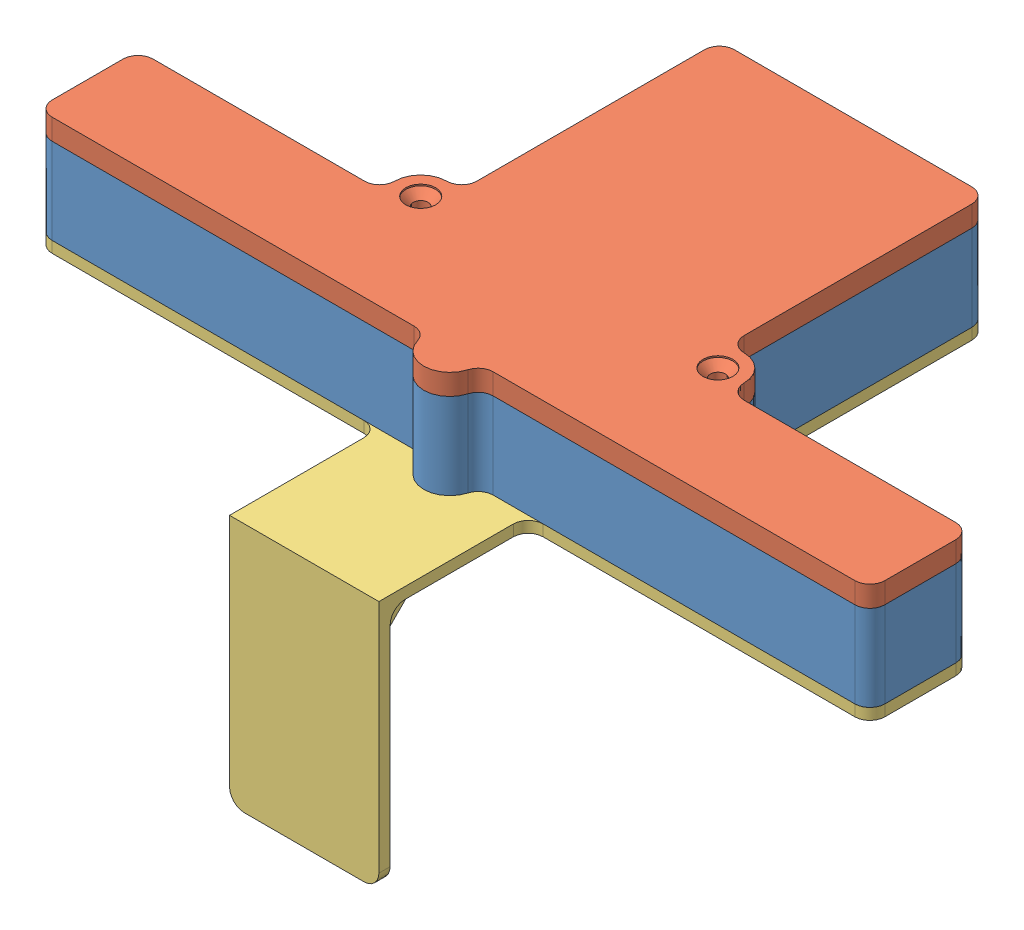
SolidWorks assembly frame, configuration Default. Lengths in mm.
Overall size (111.5 47.8 73.5).
3 component instances, 3 part files, 8 mates.
Components (placement in the parent):
- frame-front-1: frame-front [Default] at origin size (111.5 11.5 57.5)
- frame-screen-1: frame-screen [Default] at (0 11.5 0) x (1 0 0) z (0 1 0) size (111.5 57.5 2.8)
- frame-rear-1: frame-rear [Default] x (-1 0 0) z (0 -1 0) size (111.5 73.5 33.5)
Mates (geometry in assembly coordinates):
- InPlace1: in place: plane of frame-front-1 through (0 10.7 0) normal (0 1 0); plane of ? through (0 10.7 0) normal (0 1 0); moOrthogonalPlaneRef_w of frame-front-1 through (0 10.7 0) normal (0 1 0); plane of ? through (0 10.7 0) normal (0 0 -1); plane of frame-front-1 through (0 10.7 0) normal (0 1 0); plane of ? through (0 10.7 0) normal (1 0 0); plane of frame-front-1 through (0 11.5 0) normal (0 1 0); unknown of frame-screen-1
- Coincident1: coincident: plane of frame-front-1; plane of frame-screen-1
- Coincident2: coincident: moOrthogonalPlaneRef_w of frame-front-1 through (0 11.5 0) normal (0 0 -1); plane of frame-screen-1 through (0 11.5 0) normal (0 0 -1)
- Coincident3: coincident: moOrthogonalPlaneRef_w of frame-front-1 through (0 11.5 0) normal (-1 0 0); plane of frame-screen-1 through (0 11.5 0) normal (1 0 0)
- InPlace2: in place: plane of frame-front-1 through (0 0 0) normal (0 -1 0); plane of frame-rear-1 through (0 0 0) normal (0 -1 0); plane of frame-front-1 through (0 0 0) normal (0 -1 0); plane of frame-rear-1 through (0 0 0) normal (0 0 -1); plane of frame-front-1 through (0 0 0) normal (0 -1 0); plane of frame-rear-1 through (0 0 0) normal (-1 0 0); plane of frame-front-1 through (0 0 0) normal (0 -1 0); unknown of frame-rear-1
- Coincident4: coincident: plane of frame-front-1; plane of frame-rear-1
- Coincident5: coincident: moOrthogonalPlaneRef_w of frame-front-1 through (0 0 0) normal (0 0 -1); plane of frame-rear-1 through (0 0 0) normal (0 0 -1)
- Coincident6: coincident: moOrthogonalPlaneRef_w of frame-front-1 through (0 0 0) normal (1 0 0); plane of frame-rear-1 through (0 0 0) normal (-1 0 0)
